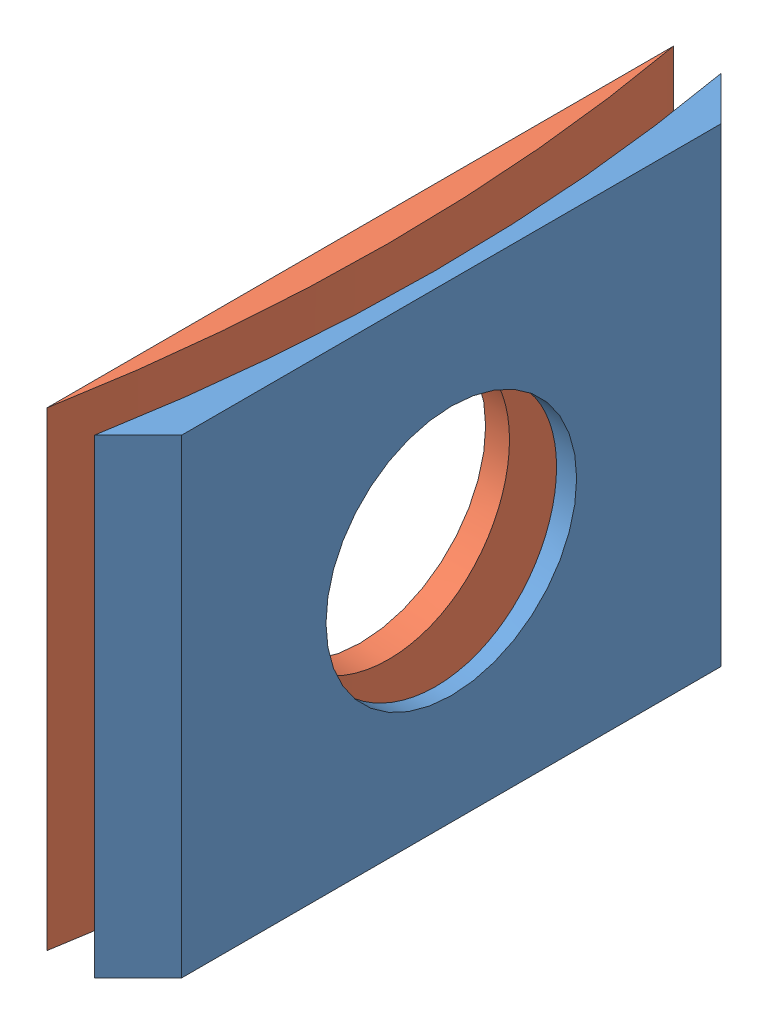
SolidWorks assembly Alignment, configuration Default. Lengths in mm.
Overall size (113.5 15 111.5).
2 component instances, 2 part files, 3 mates.
Components (placement in the parent):
- Outer Part Part-1: Outer Part Part [Default] at (-20.4997 -1.1508 -23.6312) size (1.39 15 20)
- Inner Part-1: Inner Part [Default] at (-21.2497 -1.1508 -23.6312) size (111.5 15 111.5)
Mates (geometry in assembly coordinates):
- Parallel1: parallel aligned: plane of Outer Part Part-1 through (-20.4997 13.8492 -23.6312) normal (0 1 0); plane of Inner Part-1 through (-21.2497 13.8492 -23.6312) normal (0 1 0)
- Tangent1: tangent aligned: cylinder of Outer Part Part-1 through (-20.4997 13.8492 -23.6312) axis (0 -1 0) radius 56.5; cylinder of Inner Part-1 through (-21.2497 13.8492 -23.6312) axis (0 -1 0) radius 55.75
- Concentric1: concentric anti-aligned: circle of Outer Part Part-1; circle of Inner Part-1
